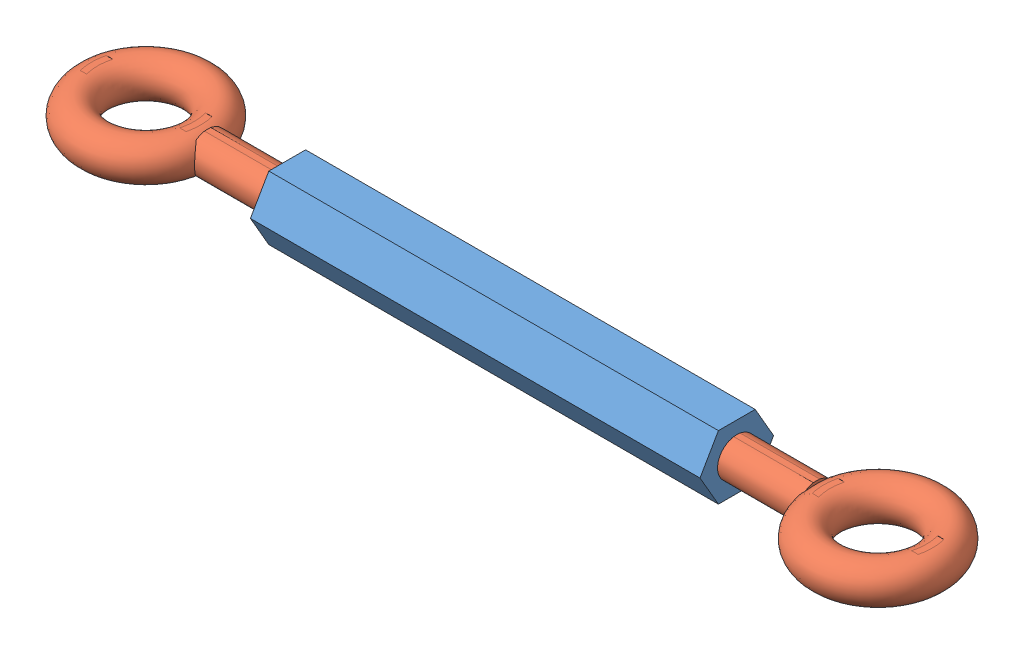
SolidWorks assembly am-3321 turnbuckle, configuration Default. Lengths in mm.
Overall size (215.9 15.75 34.92).
3 component instances, 2 part files, 0 mates.
Components (placement in the parent):
- Turnbuckle Body-1: Turnbuckle Body [Default] at (-241.5909 -75.2753 147.8583) size (111.12 15.75 18.18)
- Turnbuckle Rod-1: Turnbuckle Rod [Default] at (-200.3159 -75.2753 147.8583) x (-1 0 0) z (0 0 -1) size (93.66 9.78 34.92)
- Turnbuckle Rod-2: Turnbuckle Rod [Default] at (-171.7409 -75.2753 147.8583) size (93.66 9.78 34.92)
